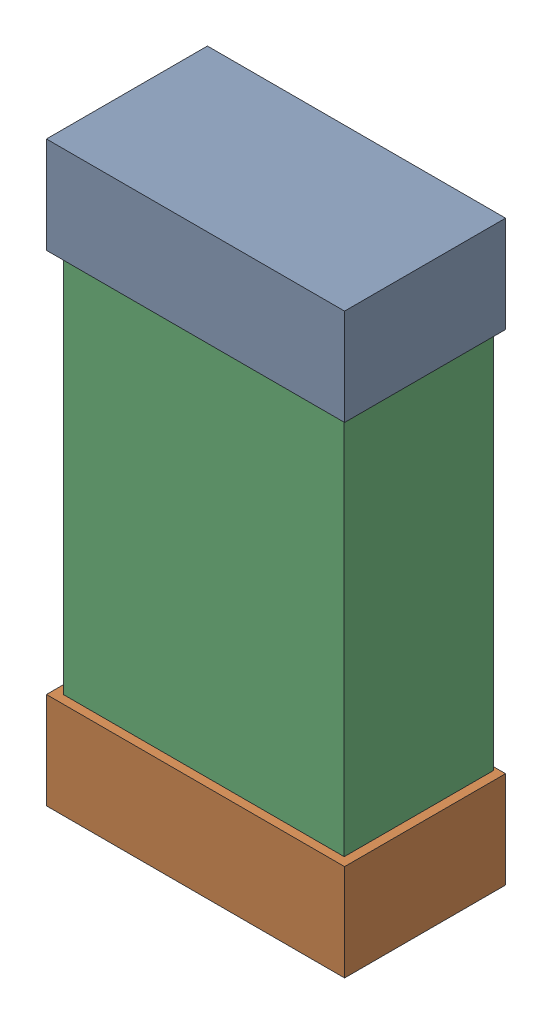
SolidWorks assembly C41, configuration Default. Lengths in mm.
Overall size (0.85 1.65 0.46).
6 component instances, 2 part files, 0 mates.
Components (placement in the parent):
- 432138512_40-1: 432138512_40 [Default] at (19.3103 50.8362 -0.8715) size (0.85 0.28 0.46)
  - Extruded-1: Extruded [Default] at origin size (0.85 0.28 0.46)
- 432138512_41-1: 432138512_41 [Default] at (19.3103 49.4647 -0.8715) size (0.85 0.28 0.46)
  - Extruded-1: Extruded [Default] at origin size (0.85 0.28 0.46)
- 432124816_20-1: 432124816_20 [Default] at (19.3103 50.1505 -0.8615) size (0.8 1.5 0.42)
  - Extruded (1)-1: Extruded (1) [Default] at origin size (0.8 1.5 0.42)
